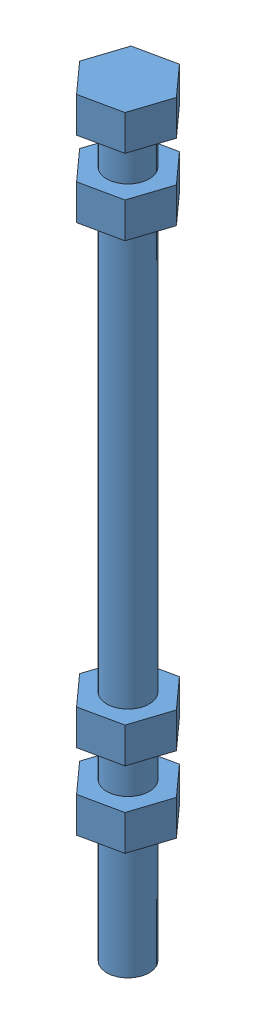
SolidWorks assembly Bolt Nut Assy, configuration Default. Lengths in mm.
Overall size (15.16 108 15.27).
4 component instances, 1 part files, 3 mates.
Components (placement in the parent):
- Bolt Nut-1: Bolt Nut [Bolt] at (44.45 98.2676 69.3699) x (-0.669131 0 -0.743145) z (-0.743145 0 0.669131) size (11.55 108 10)
- Bolt Nut-2: Bolt Nut [Nut] at (44.45 87.5526 69.3699) x (-0.669131 0 -0.743145) z (-0.743145 0 0.669131) size (11.55 5 10)
- Bolt Nut-3: Bolt Nut [Nut] at (44.45 23.215 69.3699) x (-0.669131 0 -0.743145) z (-0.743145 0 0.669131) size (11.55 5 10)
- Bolt Nut-4: Bolt Nut [Nut] at (44.45 12.5 69.3699) x (-0.669131 0 -0.743145) z (-0.743145 0 0.669131) size (11.55 5 10)
Mates (geometry in assembly coordinates):
- Concentric9: concentric: cylinder of Bolt Nut-1 through (44.45 -9.7324 69.3699) axis (0 1 0) radius 3; cylinder of Bolt Nut-2 through (44.45 82.5526 69.3699) axis (0 1 0) radius 3
- Concentric10: concentric: cylinder of Bolt Nut-1 through (44.45 -9.7324 69.3699) axis (0 1 0) radius 3; cylinder of Bolt Nut-3 through (44.45 18.215 69.3699) axis (0 1 0) radius 3
- Concentric11: concentric: cylinder of Bolt Nut-1 through (44.45 -9.7324 69.3699) axis (0 1 0) radius 3; cylinder of Bolt Nut-4 through (44.45 7.5 69.3699) axis (0 1 0) radius 3
